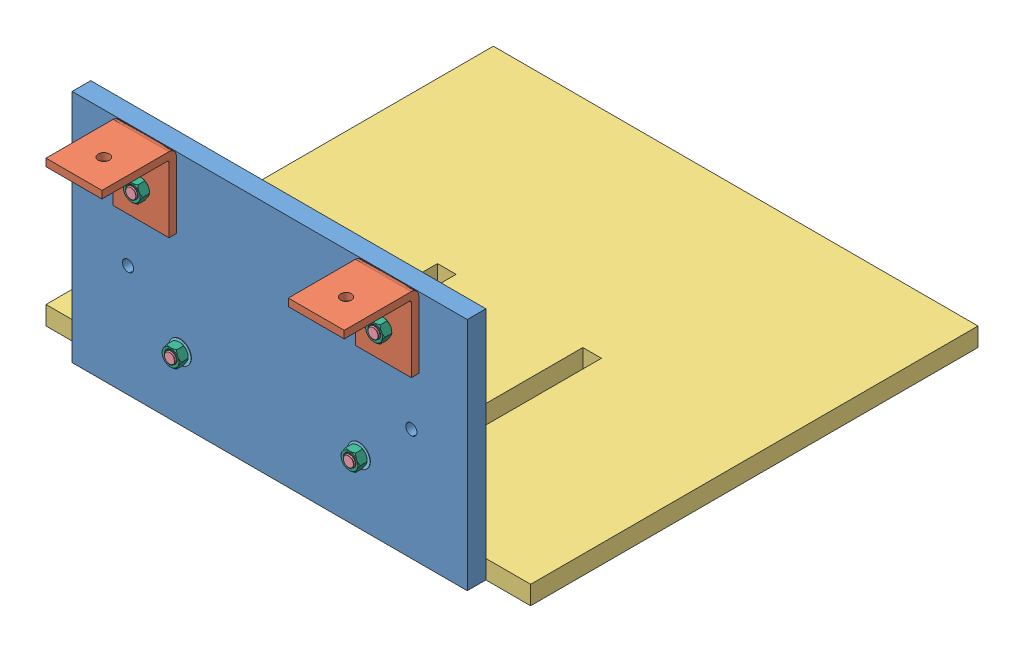
SolidWorks assembly SUBASSY_tray, configuration Default. Lengths in mm.
Overall size (130 67.21 145).
24 component instances, 6 part files, 44 mates.
Components (placement in the parent):
- tray_vertical-1: tray_vertical [Default] at (15.7462 55.3307 91.4244) size (106 63 5)
- L_bracket_beta-1: L_bracket_beta [Default] at (-9.2538 87.8307 96.4244) x (0 -1 0) z (-1 0 0) size (20 20 15)
- L_bracket_beta-2: L_bracket_beta [Default] at (55.7462 87.8307 96.4244) x (0 -1 0) z (-1 0 0) size (20 20 15)
- tray_horizontal-1: tray_horizontal [Default] at (15.7462 28.8307 31.4244) x (0 0 1) z (0 -1 0) size (120 130 5)
- bolt_phillips_M3_10mm-1: bolt_phillips_M3_10mm [Default] at (-16.7538 75.8307 91.3244) x (-1 0 0) z (0 0 -1) size (5.71 4.5 12.21)
- bolt_phillips_M3_10mm-2: bolt_phillips_M3_10mm [Default] at (48.2462 75.8307 91.3244) x (-1 0 0) z (0 0 -1) size (5.71 4.5 12.21)
- washer_M3-1: washer_M3 [Default] at (-16.7538 75.8307 91.3244) size (6 6 0.1)
- washer_M3-2: washer_M3 [Default] at (48.2462 75.8307 91.3244) size (6 6 0.1)
- nut_M3-1: nut_M3 [Default] at (-16.7538 75.8307 98.4244) size (5.71 4.5 2.74)
- nut_M3-2: nut_M3 [Default] at (48.2462 75.8307 98.4244) size (5.71 4.5 2.74)
- L_bracket_beta-3: L_bracket_beta [Default] at (32.2462 28.8307 91.4244) x (0 0 -1) z (1 0 0) size (20 20 15)
- L_bracket_beta-4: L_bracket_beta [Default] at (-15.7538 28.8307 91.4244) x (0 0 -1) z (1 0 0) size (20 20 15)
- bolt_phillips_M3_10mm-3: bolt_phillips_M3_10mm [Default] at (-8.2538 40.8307 89.4244) x (-1 0 0) z (0 0 -1) size (5.71 4.5 12.21)
- bolt_phillips_M3_10mm-4: bolt_phillips_M3_10mm [Default] at (39.7462 40.8307 89.4244) x (-1 0 0) z (0 0 -1) size (5.71 4.5 12.21)
- washer_M3-3: washer_M3 [Default] at (-8.2538 40.8307 96.4244) size (6 6 0.1)
- washer_M3-4: washer_M3 [Default] at (39.7462 40.8307 96.4244) size (6 6 0.1)
- bolt_phillips_M3_10mm-5: bolt_phillips_M3_10mm [Default] at (39.7462 30.8307 79.4244) x (0 0 -1) z (0 1 0) size (5.71 4.5 12.21)
- bolt_phillips_M3_10mm-6: bolt_phillips_M3_10mm [Default] at (-8.2538 30.8307 79.4244) x (0 0 -1) z (0 1 0) size (5.71 4.5 12.21)
- washer_M3-5: washer_M3 [Default] at (-8.2538 23.8307 79.4244) x (-1 0 0) z (0 -1 0) size (6 6 0.1)
- washer_M3-6: washer_M3 [Default] at (39.7462 23.8307 79.4244) x (-1 0 0) z (0 -1 0) size (6 6 0.1)
- nut_M3-5: nut_M3 [Default] at (-8.2538 23.7307 79.4244) x (-1 0 0) z (0 -1 0) size (5.71 4.5 2.74)
- nut_M3-6: nut_M3 [Default] at (-8.2538 40.8307 96.5244) size (5.71 4.5 2.74)
- nut_M3-7: nut_M3 [Default] at (39.7462 40.8307 96.5244) size (5.71 4.5 2.74)
- nut_M3-8: nut_M3 [Default] at (39.7462 23.7307 79.4244) x (-1 0 0) z (0 -1 0) size (5.71 4.5 2.74)
Mates (geometry in assembly coordinates):
- Coincident1: coincident aligned: circle of tray_vertical-1; circle of L_bracket_beta-1
- Coincident2: coincident aligned: circle of tray_vertical-1; circle of L_bracket_beta-2
- Parallel1: parallel anti-aligned: plane of tray_vertical-1 through (15.7462 55.3307 91.4244) normal (1 0 0); plane of L_bracket_beta-1 through (-9.2538 87.8307 96.4244) normal (-1 0 0)
- Parallel2: parallel anti-aligned: plane of tray_vertical-1 through (15.7462 55.3307 91.4244) normal (1 0 0); plane of L_bracket_beta-2 through (55.7462 87.8307 96.4244) normal (-1 0 0)
- Coincident11: coincident anti-aligned: line of tray_vertical-1 through (-37.2538 23.8307 91.4244) axis (1 0 0); line of tray_horizontal-1 through (80.7462 23.8307 91.4244) axis (-1 0 0)
- Coincident13: coincident aligned: line of tray_vertical-1 through (15.7462 86.8307 91.4244) axis (0 -1 0); line of tray_horizontal-1 through (15.7462 28.8307 91.4244) axis (0 -1 0)
- Coincident18: coincident aligned: circle of tray_vertical-1; circle of washer_M3-2
- Coincident19: coincident aligned: circle of tray_vertical-1; circle of washer_M3-1
- Parallel5: parallel aligned: plane of tray_vertical-1 through (15.7462 55.3307 91.4244) normal (1 0 0); plane of washer_M3-1 through (-16.7538 75.8307 91.3244) normal (1 0 0)
- Parallel6: parallel aligned: plane of tray_vertical-1 through (15.7462 55.3307 91.4244) normal (1 0 0); plane of washer_M3-2 through (48.2462 75.8307 91.3244) normal (1 0 0)
- Parallel3: parallel anti-aligned: plane of tray_vertical-1 through (15.7462 55.3307 91.4244) normal (1 0 0); plane of bolt_phillips_M3_10mm-1 through (-16.7538 75.8307 91.3244) normal (-1 0 0)
- Parallel4: parallel anti-aligned: plane of tray_vertical-1 through (15.7462 55.3307 91.4244) normal (1 0 0); plane of bolt_phillips_M3_10mm-2 through (48.2462 75.8307 91.3244) normal (-1 0 0)
- Coincident14: coincident anti-aligned: circle of washer_M3-1; circle of bolt_phillips_M3_10mm-1
- Coincident15: coincident anti-aligned: circle of washer_M3-2; circle of bolt_phillips_M3_10mm-2
- Coincident22: coincident aligned: circle of L_bracket_beta-1; circle of nut_M3-1
- Coincident23: coincident aligned: circle of L_bracket_beta-2; circle of nut_M3-2
- Parallel7: parallel anti-aligned: plane of L_bracket_beta-1 through (-9.2538 87.8307 96.4244) normal (-1 0 0); plane of nut_M3-1 through (-16.7538 75.8307 98.4244) normal (1 0 0)
- Parallel8: parallel anti-aligned: plane of L_bracket_beta-2 through (55.7462 87.8307 96.4244) normal (-1 0 0); plane of nut_M3-2 through (48.2462 75.8307 98.4244) normal (1 0 0)
- Coincident26: coincident anti-aligned: circle of tray_vertical-1; circle of L_bracket_beta-3
- Coincident27: coincident anti-aligned: circle of tray_vertical-1; circle of L_bracket_beta-4
- Coincident28: coincident aligned: circle of L_bracket_beta-4; circle of bolt_phillips_M3_10mm-3
- Coincident29: coincident aligned: circle of L_bracket_beta-3; circle of bolt_phillips_M3_10mm-4
- Parallel9: parallel anti-aligned: plane of tray_vertical-1 through (15.7462 55.3307 91.4244) normal (1 0 0); plane of bolt_phillips_M3_10mm-3 through (-8.2538 40.8307 89.4244) normal (-1 0 0)
- Parallel10: parallel anti-aligned: plane of tray_vertical-1 through (15.7462 55.3307 91.4244) normal (1 0 0); plane of bolt_phillips_M3_10mm-4 through (39.7462 40.8307 89.4244) normal (-1 0 0)
- Coincident32: coincident aligned: circle of tray_vertical-1; circle of washer_M3-4
- Coincident33: coincident aligned: circle of tray_vertical-1; circle of washer_M3-3
- Parallel11: parallel aligned: plane of tray_vertical-1 through (15.7462 55.3307 91.4244) normal (1 0 0); plane of washer_M3-3 through (-8.2538 40.8307 96.4244) normal (1 0 0)
- Parallel12: parallel aligned: plane of tray_vertical-1 through (15.7462 55.3307 91.4244) normal (1 0 0); plane of washer_M3-4 through (39.7462 40.8307 96.4244) normal (1 0 0)
- Coincident36: coincident aligned: circle of L_bracket_beta-3; circle of bolt_phillips_M3_10mm-5
- Coincident37: coincident aligned: circle of L_bracket_beta-4; circle of bolt_phillips_M3_10mm-6
- Parallel13: parallel aligned: plane of tray_horizontal-1 through (15.7462 28.8307 31.4244) normal (-1 0 0); plane of bolt_phillips_M3_10mm-5 through (39.7462 30.8307 79.4244) normal (-1 0 0)
- Parallel14: parallel aligned: plane of tray_horizontal-1 through (15.7462 28.8307 31.4244) normal (-1 0 0); plane of bolt_phillips_M3_10mm-6 through (-8.2538 30.8307 79.4244) normal (-1 0 0)
- Coincident40: coincident aligned: circle of tray_horizontal-1; circle of washer_M3-5
- Coincident41: coincident aligned: circle of tray_horizontal-1; circle of washer_M3-6
- Parallel15: parallel aligned: plane of tray_horizontal-1 through (15.7462 28.8307 31.4244) normal (-1 0 0); plane of washer_M3-5 through (-8.2538 23.8307 79.4244) normal (-1 0 0)
- Parallel16: parallel aligned: plane of tray_horizontal-1 through (15.7462 28.8307 31.4244) normal (-1 0 0); plane of washer_M3-6 through (39.7462 23.8307 79.4244) normal (-1 0 0)
- Coincident45: coincident aligned: circle of washer_M3-6; circle of nut_M3-8
- Coincident52: coincident aligned: circle of washer_M3-5; circle of nut_M3-5
- Parallel17: parallel aligned: plane of tray_horizontal-1 through (15.7462 28.8307 31.4244) normal (-1 0 0); plane of nut_M3-5 through (-8.2538 23.7307 79.4244) normal (-1 0 0)
- Parallel18: parallel aligned: plane of tray_horizontal-1 through (15.7462 28.8307 31.4244) normal (-1 0 0); plane of nut_M3-8 through (39.7462 23.7307 79.4244) normal (-1 0 0)
- Coincident48: coincident aligned: circle of washer_M3-4; circle of nut_M3-7
- Coincident49: coincident aligned: circle of washer_M3-3; circle of nut_M3-6
- Parallel19: parallel aligned: plane of tray_vertical-1 through (15.7462 55.3307 91.4244) normal (1 0 0); plane of nut_M3-7 through (39.7462 40.8307 96.5244) normal (1 0 0)
- Parallel20: parallel aligned: plane of tray_vertical-1 through (15.7462 55.3307 91.4244) normal (1 0 0); plane of nut_M3-6 through (-8.2538 40.8307 96.5244) normal (1 0 0)
